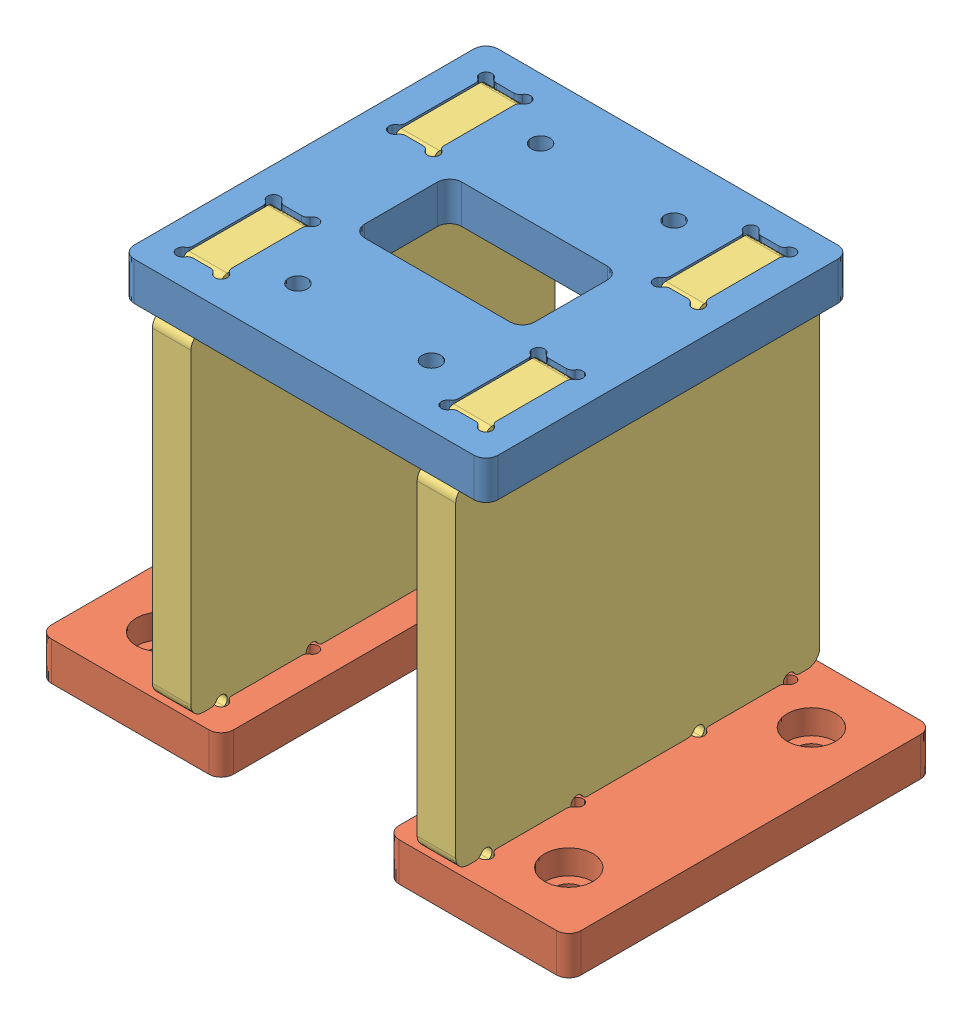
SolidWorks assembly ASSY_MOTOR_STAND_HIGH_WOOD, configuration Default. Lengths in mm.
Overall size (87.3 67.4 60).
5 component instances, 3 part files, 12 mates.
Components (placement in the parent):
- MOTOR_STAND_TOP_WOOD-1: MOTOR_STAND_TOP_WOOD [Default] at origin size (60 6.35 60)
- MOTOR_STAND_BOT_WOOD-1: MOTOR_STAND_BOT_WOOD [Default] at (-28.65 -61.05 0) size (30 6.35 60)
- MOTOR_STAND_HIGH_SIDE_WOOD-1: MOTOR_STAND_HIGH_SIDE_WOOD [Default] at (-25 -27.35 0) x (0 0 -1) z (1 0 0) size (60 66.7 6.35)
- MOTOR_STAND_BOT_WOOD-3: MOTOR_STAND_BOT_WOOD [Default] at (28.65 -61.05 0) x (-1 0 0) z (0 0 -1) size (30 6.35 60)
- MOTOR_STAND_HIGH_SIDE_WOOD-2: MOTOR_STAND_HIGH_SIDE_WOOD [Default] at (18.65 -27.35 0) x (0 0 -1) z (1 0 0) size (60 66.7 6.35)
Mates (geometry in assembly coordinates):
- Coincident1: coincident anti-aligned: plane of MOTOR_STAND_TOP_WOOD-1 through (0 0 0) normal (0 -1 0); plane of MOTOR_STAND_SIDE_WOOD-1 through (-25 0 -30) normal (0 1 0)
- Coincident2: coincident anti-aligned: plane of MOTOR_STAND_TOP_WOOD-1 through (-25 0 -11.7321) normal (1 0 0); plane of MOTOR_STAND_SIDE_WOOD-1 through (-25 -5 0) normal (-1 0 0)
- Coincident3: coincident anti-aligned: plane of MOTOR_STAND_TOP_WOOD-1 through (-23.2679 0 25) normal (0 0 -1); plane of MOTOR_STAND_SIDE_WOOD-1 through (-2.4945 0 25) normal (0 0 1)
- Coincident4: coincident anti-aligned: plane of MOTOR_STAND_BOT_WOOD-1 through (-18.65 -36.75 25) normal (-1 0 0); plane of MOTOR_STAND_SIDE_WOOD-1 through (-18.65 -5 0) normal (1 0 0)
- Coincident5: coincident anti-aligned: plane of MOTOR_STAND_BOT_WOOD-1 through (-28.65 -30.4 0) normal (0 1 0); plane of MOTOR_STAND_SIDE_WOOD-1 through (-25 -10 -30) normal (0 -1 0)
- Coincident6: coincident anti-aligned: plane of MOTOR_STAND_BOT_WOOD-1 through (-25 -36.75 25) normal (0 0 -1); plane of MOTOR_STAND_SIDE_WOOD-1 through (-2.4945 -10 25) normal (0 0 1)
- Coincident7: coincident anti-aligned: plane of MOTOR_STAND_TOP_WOOD-1 through (-18.65 0 23.2679) normal (-1 0 0); plane of MOTOR_STAND_HIGH_SIDE_WOOD-1 through (-18.65 -27.35 0) normal (1 0 0)
- Coincident8: coincident anti-aligned: plane of MOTOR_STAND_BOT_WOOD-1 through (-18.65 -61.05 25) normal (-1 0 0); plane of MOTOR_STAND_HIGH_SIDE_WOOD-1 through (-18.65 -27.35 0) normal (1 0 0)
- Coincident9: coincident anti-aligned: plane of MOTOR_STAND_TOP_WOOD-1 through (0 0 0) normal (0 -1 0); plane of MOTOR_STAND_HIGH_SIDE_WOOD-1 through (-18.65 0 30) normal (0 1 0)
- Coincident10: coincident anti-aligned: plane of MOTOR_STAND_BOT_WOOD-1 through (-28.65 -54.7 0) normal (0 1 0); plane of MOTOR_STAND_HIGH_SIDE_WOOD-1 through (-18.65 -54.7 30) normal (0 -1 0)
- Coincident11: coincident anti-aligned: plane of MOTOR_STAND_TOP_WOOD-1 through (-23.2679 0 -25) normal (0 0 1); plane of MOTOR_STAND_HIGH_SIDE_WOOD-1 through (-41.1555 0 -25) normal (0 0 -1)
- Coincident12: coincident anti-aligned: plane of MOTOR_STAND_BOT_WOOD-1 through (-25 -61.05 -25) normal (0 0 1); plane of MOTOR_STAND_HIGH_SIDE_WOOD-1 through (-41.1555 -54.7 -25) normal (0 0 -1)
